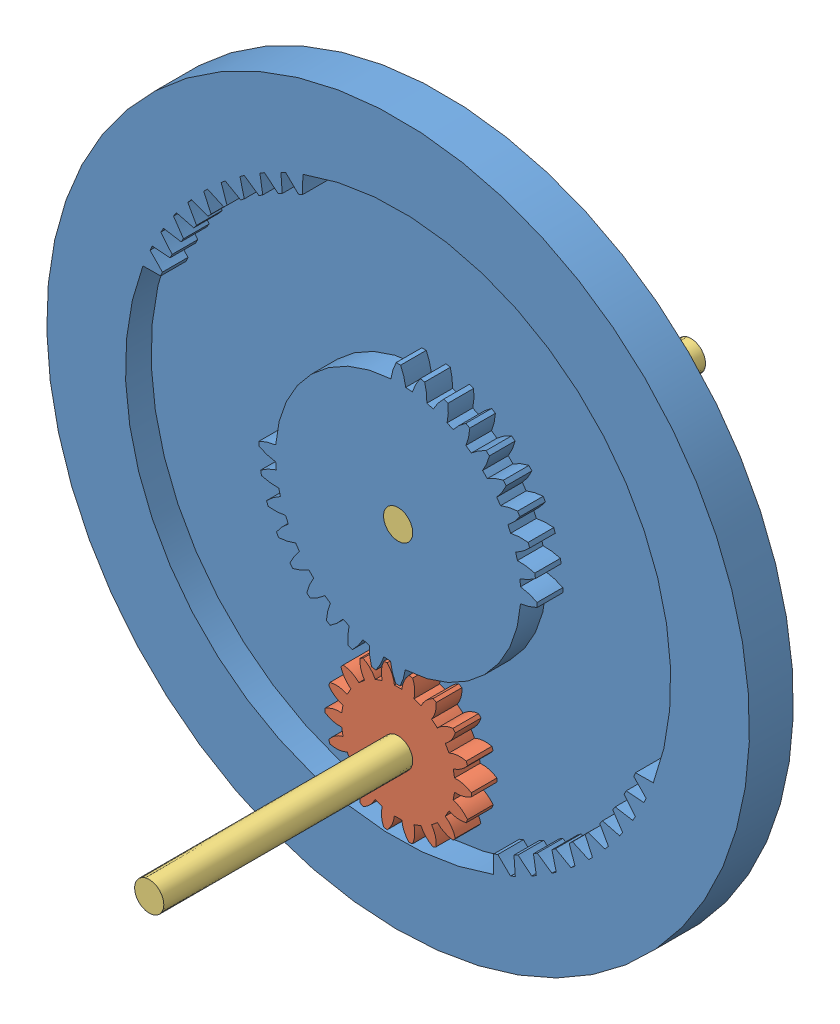
SolidWorks assembly mother_child, configuration Default. Lengths in mm.
Overall size (117.45 117.45 74).
4 component instances, 3 part files, 9 mates.
Components (placement in the parent):
- motherGear_36t72t-1: motherGear_36t72t [Default] at (0 0 14.5) x (-0.966407 -0.257018 0) z (0 0 -1) size (96 96 6)
- childGear_18t-1: childGear_18t [Default] at (0 -27 2.5) size (20 19.78 3.5)
- shaft_ip-1: shaft_ip [Default] at (0 0 -34) size (4 4 40)
- shaft_ip-2: shaft_ip [Default] at (0 -27 0) size (4 4 40)
Mates (geometry in assembly coordinates):
- Coincident2: coincident: plane of assembly through (0 0 0) normal (0 0 1); plane of motherGear_36t72t-1 through (0 0 0) normal (0 0 -1); plane of assembly
- Concentric1: concentric: cylinder of assembly; cylinder of motherGear_36t72t-1 through (0 0 141.7645) axis (0 0 -1) radius 48; circle of assembly
- Coincident3: coincident: plane of assembly; plane of assembly; plane of motherGear_36t72t-1 through (0 0 2.5) normal (0 0 1); plane of childGear_18t-1 through (0 -27 2.5) normal (0 0 -1)
- Concentric2: concentric: cylinder of assembly; cylinder of childGear_18t-1 through (0 -27 -35.5001) axis (0 0 1) radius 2; circle of assembly
- Coincident4: coincident: plane of assembly; plane of assembly; plane of motherGear_36t72t-1 through (0 0 6) normal (0 0 1); plane of shaft_ip-1 through (0 0 6) normal (0 0 1)
- Concentric3: concentric: cylinder of assembly; cylinder of assembly; cylinder of motherGear_36t72t-1 through (0 0 0) axis (0 0 1) radius 2; cylinder of shaft_ip-1 through (0 0 6) axis (0 0 -1) radius 2
- Coincident5: coincident: plane of assembly; plane of assembly; plane of motherGear_36t72t-1 through (0 0 0) normal (0 0 -1); plane of shaft_ip-2 through (0 -27 0) normal (0 0 -1)
- Concentric4: concentric: cylinder of assembly; cylinder of assembly; cylinder of childGear_18t-1 through (0 -27 -35.5001) axis (0 0 1) radius 2; cylinder of shaft_ip-2 through (0 -27 40) axis (0 0 -1) radius 2
- Concentric5: concentric: cylinder of shaft_ip-2 through (0 -27 40) axis (0 0 -1) radius 2; cylinder of ? through (0 -27 -18.3793) axis (0 0 1) radius 2
